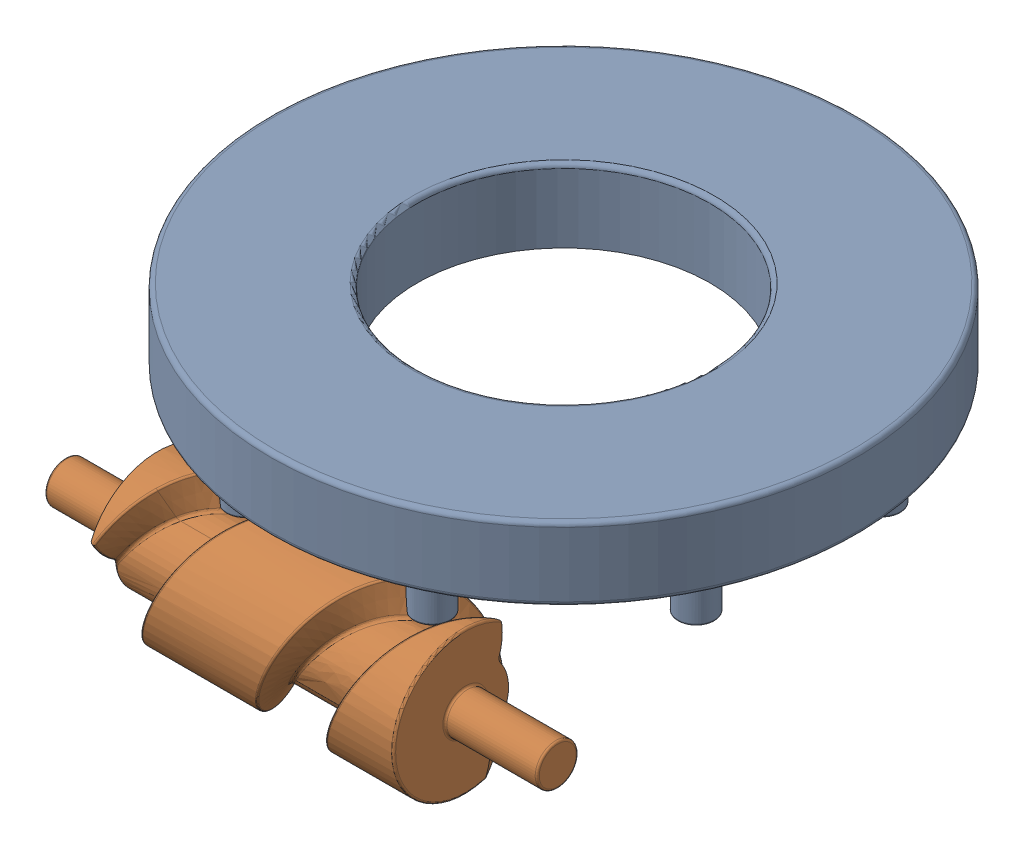
SolidWorks assembly Assembly Of Rotating Table Working Copy, configuration Default. Lengths in mm.
Overall size (4015.16 1818.88 4398.05).
2 component instances, 2 part files, 5 mates.
Components (placement in the parent):
- Rotating Table-1: Rotating Table [Default] at (0 350 0) x (0.999993 0 -0.003798) z (0.003798 0 0.999993) size (4000 850 4000)
- Driving Shaft-1: Driving Shaft [Default] at (0 -310.8256 1715.3852) x (1 0 0) z (0 -0.921471 -0.388447) size (3360 1020.93 1022.29)
Mates (geometry in assembly coordinates):
- Concentric1: concentric anti-aligned: circle of Rotating Table-1
- Coincident1: coincident anti-aligned: plane of Rotating Table-1 through (-641.8116 0 1537.5435) normal (0 -1 0)
- Coincident2: coincident aligned: line of Rotating Table-1 through (-467.5 0 350) axis (0 1 0)
- Concentric2: concentric aligned: cylinder of Driving Shaft-1 through (-1680.0377 -300 1720) axis (1 0 0) radius 140
- Coincident3: coincident aligned: plane of Driving Shaft-1 through (0 -308.7062 1727.9179) normal (1 0 0)
